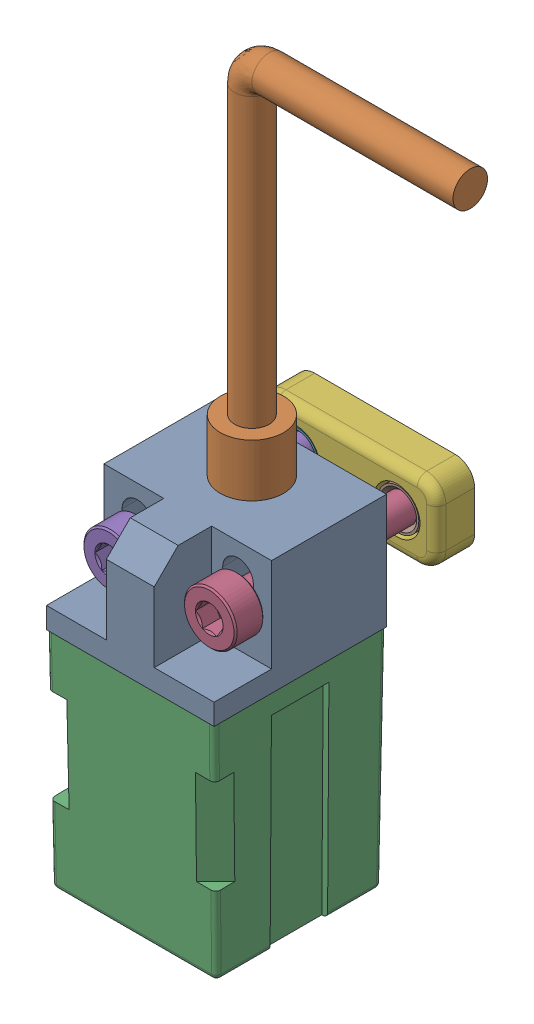
SolidWorks assembly PL-08N v3, configuration Default. Lengths in mm.
Overall size (32.15 74.5 26.6).
10 component instances, 6 part files, 0 mates.
Components (placement in the parent):
- PL-08N v3_2-1: PL-08N v3_2 [Default] at origin size (31.55 74.5 18)
  - PL-08N v3_3-1: PL-08N v3_3 [Default] at origin size (17.5 12 18)
  - PL-08N v3_2-1: PL-08N v3_2 [Default] at origin size (26.1 51.1 6.6)
  - PL-08N v3-1: PL-08N v3 [Default] at origin size (17.5 23.4 18)
- M3x20 SHCS (1)-1: M3x20 SHCS (1) [Default] at (5.25 29.9 -36.75) x (0 1 0) z (0 0 -1) size (5.5 5.5 23.14)
- M3x20 SHCS (1)-2: M3x20 SHCS (1) [Default] at (-5.25 29.9 -36.75) x (0 1 0) z (0 0 -1) size (5.5 5.5 23.14)
- probe_bracket-1: probe_bracket [Default] at (-128.542 31.5573 54.6791) x (0 0 1) z (0 1 0) size (4 18.7 8.2)
  - probe_bracket-1: probe_bracket [Default] at origin size (4 18.7 8.2)
  - M3 Threaded Insert (1)-1: M3 Threaded Insert (1) [Default] at (-68.1791 123.292 -1.6573) x (0 1 0) z (-1 0 0) size (5 5 3.85)
  - M3 Threaded Insert (1)-2: M3 Threaded Insert (1) [Default] at (-68.1791 133.792 -1.6573) x (0 1 0) z (-1 0 0) size (5 5 3.85)
